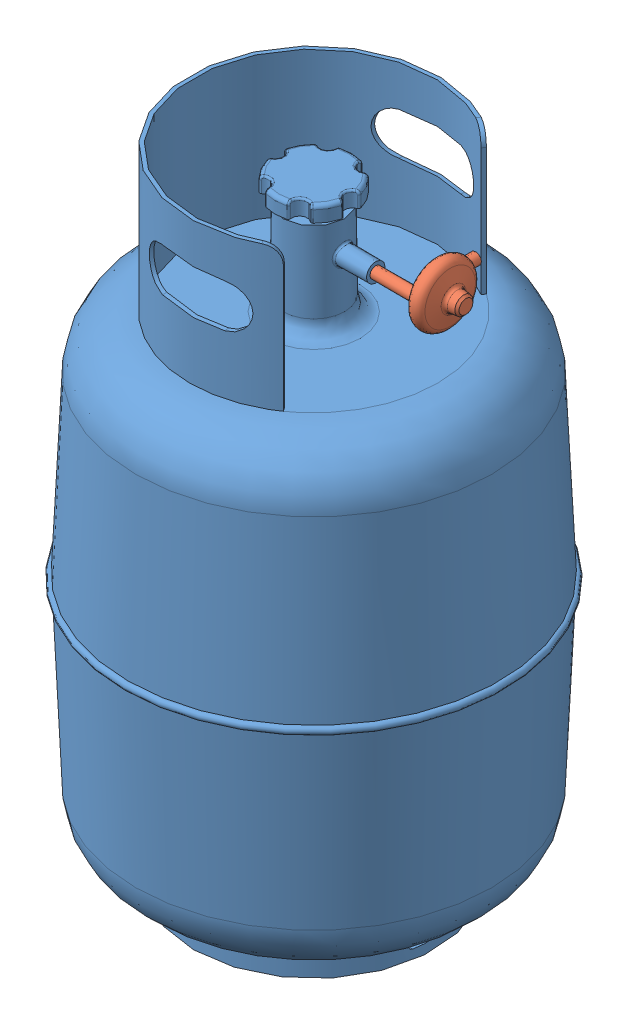
SolidWorks assembly Tank_and_Regulator, configuration Default. Lengths in mm.
Overall size (311.15 521.42 311.15).
2 component instances, 2 part files, 3 mates.
Components (placement in the parent):
- tank_20lb_propane-1: tank_20lb_propane [Default] at origin
- regulator-1: regulator [Default] at (86.675 431.8 -12.7) x (0 -1 0) z (0 0 1)
Mates (geometry in assembly coordinates):
- Concentric1: concentric anti-aligned: cylinder of tank_20lb_propane-1 through (50.8 431.8 0) axis (-1 0 0) radius 7.7; cylinder of regulator-1 through (38.1 431.8 0) axis (1 0 0) radius 3.9688
- Coincident1: coincident anti-aligned: plane of tank_20lb_propane-1 through (50.8 431.8 0) normal (1 0 0); circle of regulator-1
- Parallel1: parallel anti-aligned: plane of regulator-1 through (86.675 431.8 -12.7) normal (0 -1 0); plane of assembly through (0 0 0) normal (0 1 0)
